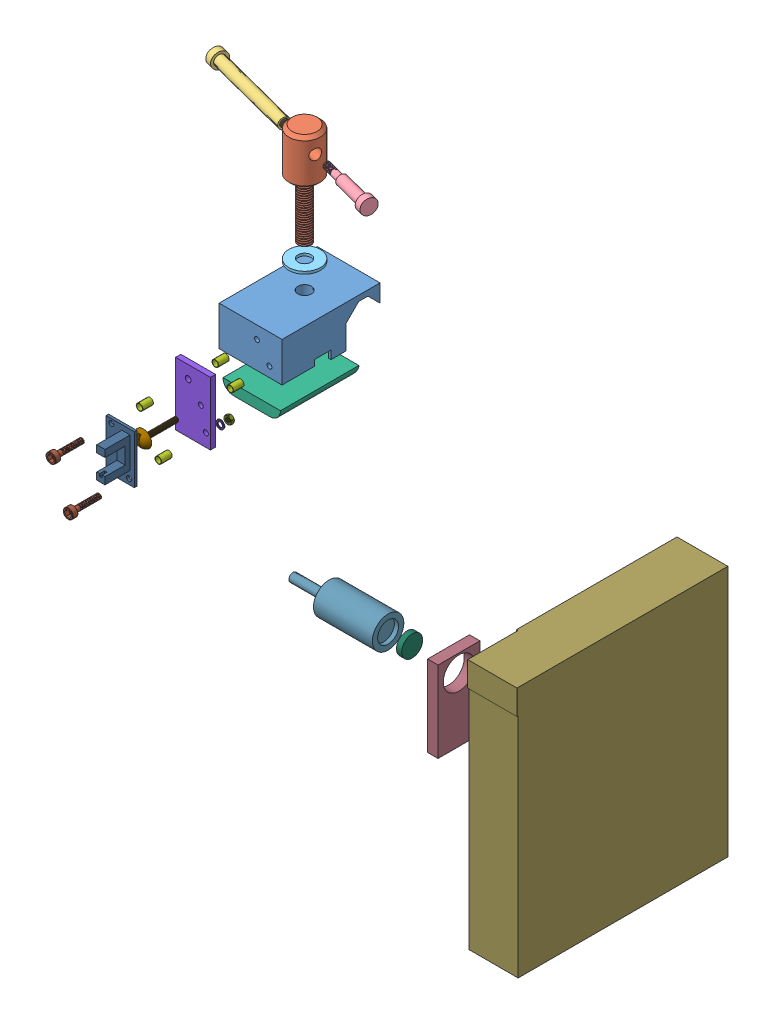
SolidWorks assembly carriage autostop, configuration Default. Lengths in mm.
Overall size (345.89 240.72 184.46).
21 component instances, 17 part files, 23 mates.
Components (placement in the parent):
- body-1: body [Default] at (25.7891 19.8311 72.3301) size (38.1 25.43 59.36)
- shaft-1: shaft [Default] at (25.7891 70.6921 39.6149) x (0.251457 0 -0.967869) z (0.967869 0 0.251457) size (19.05 61.86 19.05)
- T-handle female-1: T-handle female [Default] at (-47.2226 122.1601 20.6462) x (0.967869 0 0.251457) z (-0.251245 -0.040998 0.967055) size (58.35 9.53 9.53)
- T-handle male-1: T-handle male [Default] at (43.925 122.1601 44.3267) x (0.967869 0 0.251457) z (-0.251457 0 0.967869) size (36.12 9.08 9.08)
- washer-2: washer [Default] at (25.7891 60.2707 39.6149) x (0.99451 0 -0.104646) z (0.104646 0 0.99451) size (19.05 1.52 19.05)
- clamp-2: clamp [Default] at (25.7891 0.2864 47.8699) x (0 0 -1) z (1 0 0) size (47.5 6.6 34.8)
- spacer-1: spacer [Default] at (29.5991 37.5749 91.1079) size (4 4 6.35)
- spacer-2: spacer [Default] at (37.2191 27.4149 89.77) size (4 4 6.35)
- PCB carrier-1: PCB carrier [Default] at (21.9791 7.0949 110.7128) x (1 0 0) z (0 -1 0) size (21.08 3.17 38.1)
- RH M3-05-1: RH M3-05 [Default] at (37.2191 27.6689 128.6995) x (0.999063 0.04327 0) z (0 0 -1) size (10.1 10.1 23.45)
- spacer-4: spacer [Default] at (40.2791 14.7449 136.3118) x (0.917902 -0.396808 0) z (0 0 1) size (4 4 6.35)
- spacer-5: spacer [Default] at (29.5991 37.5749 137.0063) x (0.991039 -0.133573 0) z (0 0 1) size (4 4 6.35)
- PI on board-1: PI on board [Default] at (35.9191 37.1949 160.4012) x (0 -1 0) z (-1 0 0) size (29.31 16.72 17.04)
- SHCS M3-05-1: SHCS M3-05 [Default] at (29.5991 37.5749 178.299) x (-0.863299 -0.504693 0) z (0 0 -1) size (6 6 19.14)
- SHCS M3-05-2: SHCS M3-05 [Default] at (40.2791 13.9849 178.5332) x (-0.820811 -0.5712 0) z (0 0 -1) size (6 6 19.14)
- carriage-1: carriage [Default] at (267.5514 -108.5592 118.4283) size (30.81 152.4 127.71)
- guide-1: guide [Default] at (245.4836 9.7184 172.1479) size (6.35 49.02 25.4)
- probe-1: probe [Default] at (151.339 23.7032 172.1479) size (57.56 19.05 19.05)
- magnet-1: magnet [Default] at (220.3115 23.7032 172.1479) size (3.17 12.7 12.7)
- nut-1: nut [Default] at (40.2791 14.7449 99.7775) x (0 0 1) z (-0.760231 -0.649653 0) size (2.37 5.33 5.05)
- small washer-1: small washer [Default] at (40.2791 14.7449 104.8969) x (0.987848 0.155424 0) z (0 0 1) size (5 5 0.5)
Mates (geometry in assembly coordinates):
- Concentric4: concentric anti-aligned: circle of body-1; cylinder of washer-2 through (25.7891 61.7947 39.6149) axis (0 -1 0) radius 3.937
- Concentric8: concentric anti-aligned: cylinder of spacer-1 through (29.5991 37.5749 91.1079) axis (0 0 1) radius 1.75; cylinder of PCB carrier-1 through (29.5991 37.5749 113.8878) axis (0 0 -1) radius 1.75
- Parallel8: parallel aligned: plane of body-1 through (44.8391 21.2936 72.3047) normal (0 0 1); plane of PCB carrier-1 through (21.9791 7.0949 113.8878) normal (0 0 1)
- Parallel11: parallel aligned: line of body-1 through (44.8391 45.1949 72.3047) axis (-1 0 0); line of PCB carrier-1 through (43.0611 45.1949 113.8878) axis (-1 0 0)
- Concentric18: concentric anti-aligned: cylinder of PCB carrier-1 through (40.2791 14.7449 113.8878) axis (0 0 -1) radius 1.5; cylinder of spacer-4 through (40.2791 14.7449 136.3118) axis (0 0 1) radius 1.75
- Concentric19: concentric anti-aligned: cylinder of PCB carrier-1 through (29.5991 37.5749 113.8878) axis (0 0 -1) radius 1.75; cylinder of spacer-5 through (29.5991 37.5749 137.0063) axis (0 0 1) radius 1.75
- Concentric21: concentric aligned: cylinder of spacer-5 through (29.5991 37.5749 137.0063) axis (0 0 1) radius 1.75; cylinder of PI on board-1 through (29.5991 37.5749 158.8772) axis (0 0 1) radius 1.5
- Concentric22: concentric anti-aligned: cylinder of PI on board-1 through (29.5991 37.5749 158.8772) axis (0 0 1) radius 1.5; cylinder of SHCS M3-05-1 through (29.5991 37.5749 178.299) axis (0 0 -1) radius 1.5
- Coincident5: coincident anti-aligned: circle of PI on board-1; cylinder of SHCS M3-05-2 through (40.2791 13.9849 178.5332) axis (0 0 -1) radius 1.5
- Parallel14: parallel aligned: plane of body-1 through (44.8391 45.1949 72.3047) normal (0 1 0); plane of carriage-1 through (267.5514 43.8408 181.9283) normal (0 1 0)
- Parallel16: parallel aligned: plane of carriage-1 through (315.4637 -33.7812 181.9283) normal (0 0 1); plane of guide-1 through (251.8336 -14.7926 184.8479) normal (0 0 1)
- Concentric23: concentric aligned: cylinder of guide-1 through (251.8336 23.7032 172.1479) axis (-1 0 0) radius 9.525; cylinder of probe-1 through (151.339 23.7032 172.1479) axis (-1 0 0) radius 9.525
- Concentric24: concentric aligned: cylinder of probe-1 through (151.339 23.7032 172.1479) axis (-1 0 0) radius 6.35; cylinder of magnet-1 through (223.4865 23.7032 172.1479) axis (-1 0 0) radius 6.35
- Parallel17: parallel aligned: plane of PCB carrier-1 through (43.0611 7.0949 113.8878) normal (1 0 0); plane of PI on board-1 through (43.4591 10.8049 158.8772) normal (1 0 0)
- Concentric25: concentric aligned: cylinder of PCB carrier-1 through (40.2791 14.7449 113.8878) axis (0 0 -1) radius 1.5; cylinder of small washer-1 through (40.2791 14.7449 105.3969) axis (0 0 -1) radius 1.5
- Concentric26: concentric anti-aligned: circle of nut-1; circle of small washer-1
- Concentric27: concentric aligned: circle of shaft-1; circle of washer-2
- Concentric28: concentric anti-aligned: cylinder of shaft-1 through (16.5702 122.1601 37.2198) axis (0.967869 0 0.251457) radius 3.175; cylinder of T-handle female-1 through (-47.2226 122.1601 20.6462) axis (-0.967869 0 -0.251457) radius 3.2385
- Concentric29: concentric anti-aligned: cylinder of shaft-1 through (16.5702 122.1601 37.2198) axis (0.967869 0 0.251457) radius 3.175; cylinder of T-handle male-1 through (43.925 122.1601 44.3267) axis (-0.967869 0 -0.251457) radius 2
- Concentric30: concentric aligned: circle of body-1; circle of clamp-2
- Concentric32: concentric aligned: cylinder of PCB carrier-1 through (37.2191 27.6689 113.8878) axis (0 0 -1) radius 1.5; circle of RH M3-05-1
- Concentric35: concentric aligned: circle of body-1; circle of spacer-1
- Concentric38: concentric anti-aligned: cylinder of body-1 through (37.2191 27.4149 59.6047) axis (0 0 1) radius 1.5; cylinder of spacer-2 through (37.2191 27.4149 96.12) axis (0 0 -1) radius 2
